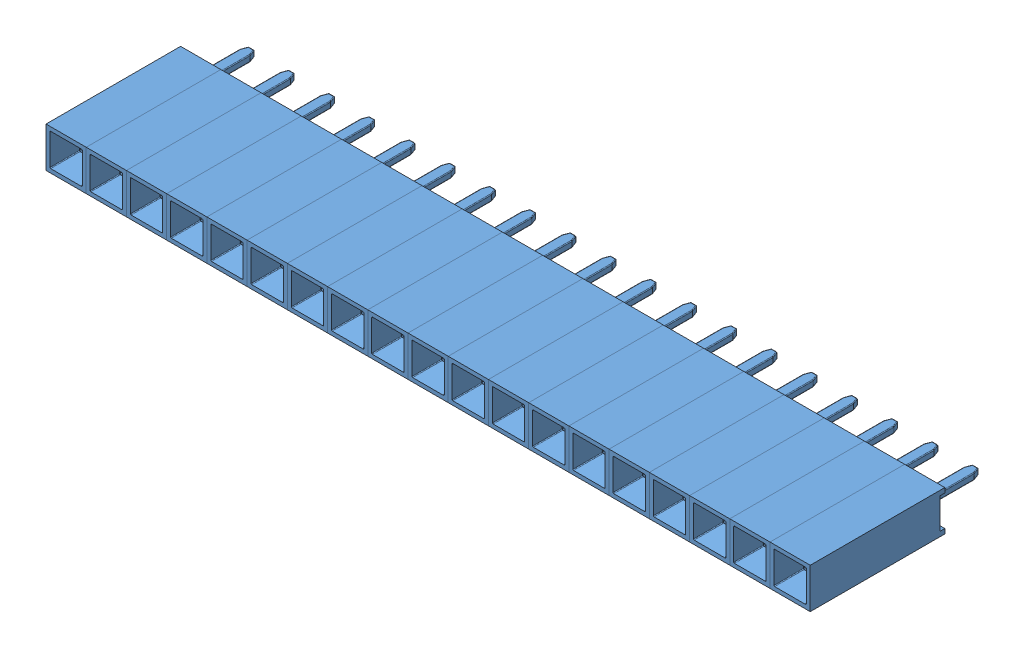
SolidWorks assembly Female Pin Header 01x19 Pitch 2.54mm Height 8.5mm.stp, configuration Valor predeterminado. Lengths in mm.
Overall size (48.26 2.54 11.7).
19 component instances, 1 part files, 0 mates.
Components (placement in the parent):
- Female Pin Header 1x.stp-1: Female Pin Header 1x.stp [Valor predeterminado] at origin size (2.54 2.54 11.7)
- Female Pin Header 1x.stp-2: Female Pin Header 1x.stp [Valor predeterminado] at (2.54 0 0) size (2.54 2.54 11.7)
- Female Pin Header 1x.stp-3: Female Pin Header 1x.stp [Valor predeterminado] at (5.08 0 0) size (2.54 2.54 11.7)
- Female Pin Header 1x.stp-4: Female Pin Header 1x.stp [Valor predeterminado] at (7.62 0 0) size (2.54 2.54 11.7)
- Female Pin Header 1x.stp-5: Female Pin Header 1x.stp [Valor predeterminado] at (10.16 0 0) size (2.54 2.54 11.7)
- Female Pin Header 1x.stp-6: Female Pin Header 1x.stp [Valor predeterminado] at (12.7 0 0) size (2.54 2.54 11.7)
- Female Pin Header 1x.stp-7: Female Pin Header 1x.stp [Valor predeterminado] at (15.24 0 0) size (2.54 2.54 11.7)
- Female Pin Header 1x.stp-8: Female Pin Header 1x.stp [Valor predeterminado] at (17.78 0 0) size (2.54 2.54 11.7)
- Female Pin Header 1x.stp-9: Female Pin Header 1x.stp [Valor predeterminado] at (20.32 0 0) size (2.54 2.54 11.7)
- Female Pin Header 1x.stp-10: Female Pin Header 1x.stp [Valor predeterminado] at (22.86 0 0) size (2.54 2.54 11.7)
- Female Pin Header 1x.stp-11: Female Pin Header 1x.stp [Valor predeterminado] at (25.4 0 0) size (2.54 2.54 11.7)
- Female Pin Header 1x.stp-12: Female Pin Header 1x.stp [Valor predeterminado] at (27.94 0 0) size (2.54 2.54 11.7)
- Female Pin Header 1x.stp-13: Female Pin Header 1x.stp [Valor predeterminado] at (30.48 0 0) size (2.54 2.54 11.7)
- Female Pin Header 1x.stp-14: Female Pin Header 1x.stp [Valor predeterminado] at (33.02 0 0) size (2.54 2.54 11.7)
- Female Pin Header 1x.stp-15: Female Pin Header 1x.stp [Valor predeterminado] at (35.56 0 0) size (2.54 2.54 11.7)
- Female Pin Header 1x.stp-16: Female Pin Header 1x.stp [Valor predeterminado] at (38.1 0 0) size (2.54 2.54 11.7)
- Female Pin Header 1x.stp-17: Female Pin Header 1x.stp [Valor predeterminado] at (40.64 0 0) size (2.54 2.54 11.7)
- Female Pin Header 1x.stp-18: Female Pin Header 1x.stp [Valor predeterminado] at (43.18 0 0) size (2.54 2.54 11.7)
- Female Pin Header 1x.stp-19: Female Pin Header 1x.stp [Valor predeterminado] at (45.72 0 0) size (2.54 2.54 11.7)
